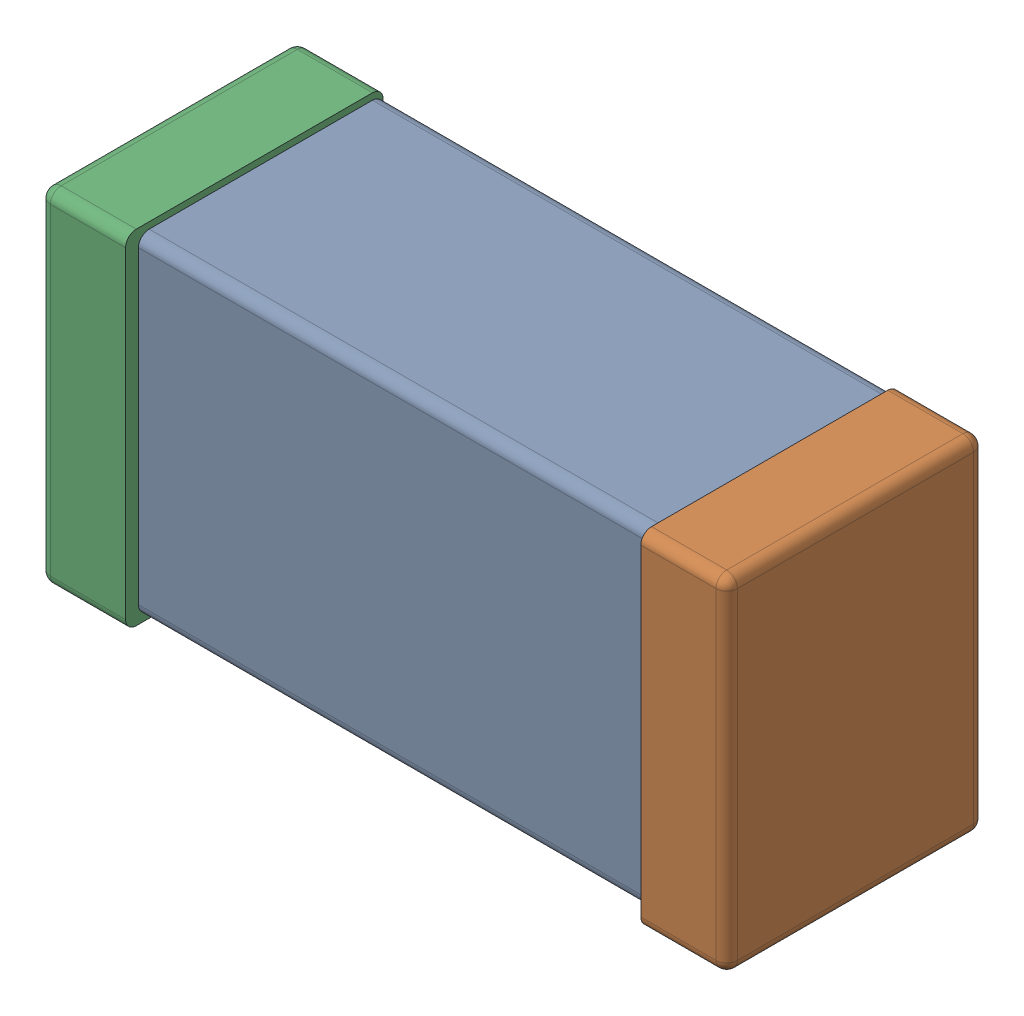
SolidWorks assembly C0603_060_6, configuration Standard. Lengths in mm.
Overall size (1.6 0.8 0.6).
4 component instances, 3 part files, 0 mates.
Components (placement in the parent):
- C0603_060_7-1: C0603_060_7 [Standard] at (0 0 23.8) size (1.6 0.8 0.6)
  - Part 3_1-1: Part 3_1 [Standard] at (0 0 -23.815) size (1.4 0.77 0.57)
  - Part 2_1-1: Part 2_1 [Standard] at (0 0 -23.8) size (0.2 0.8 0.6)
  - Part 1_1-1: Part 1_1 [Standard] at (0 0 -23.8) size (0.2 0.8 0.6)
